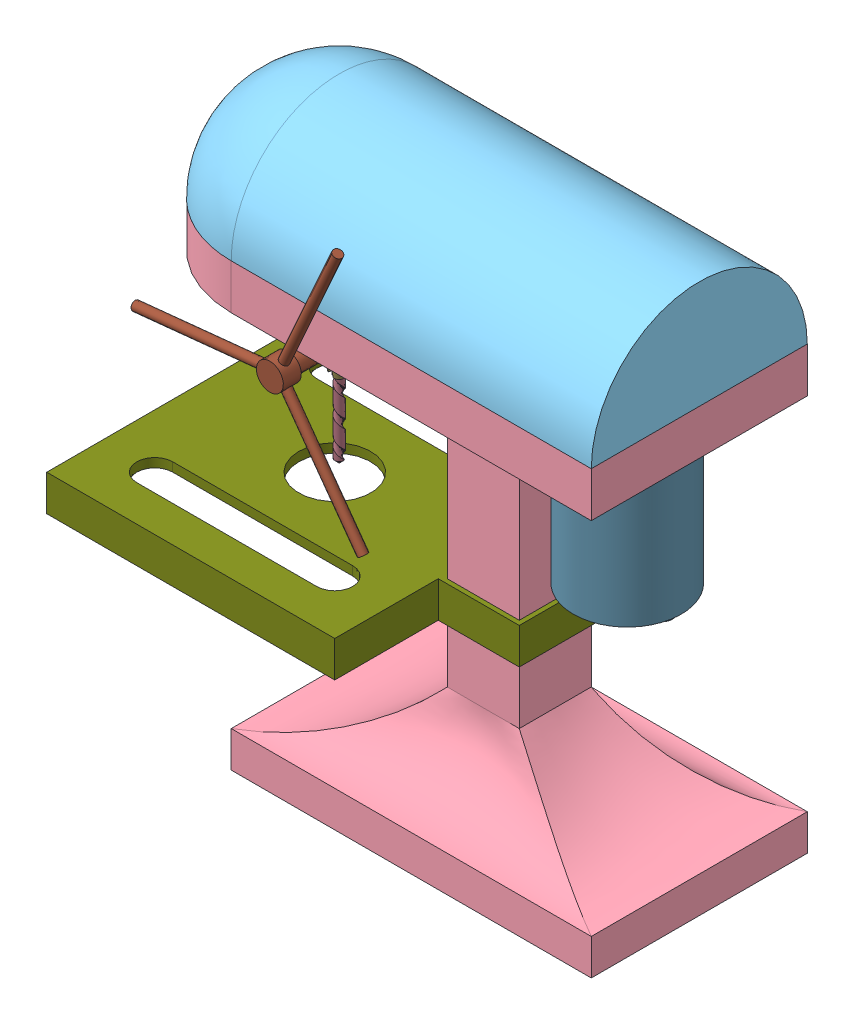
SolidWorks assembly Drill_Press, configuration Default. Lengths in mm.
Overall size (179.6 193.68 101.6).
16 component instances, 16 part files, 33 mates.
Components (placement in the parent):
- drill_slider-1: drill_slider [Default] at (-63.5 37.4244 0) size (19.05 50.8 19.05)
- drill_top_shaft-1: drill_top_shaft [Default] at (-63.5 28.575 0) x (0.204531 0 0.97886) z (-0.97886 0 0.204531) size (19.05 60.32 19.05)
- drill_bottom_shaft-2: drill_bottom_shaft [Default] at (-63.5 35.8369 0) x (0.204531 0 0.97886) z (-0.97886 0 0.204531) size (12.7 50.8 12.7)
- drill_body-1: drill_body [Default] at origin size (165.1 155.58 76.2)
- drill_lid-1: drill_lid [Default] at (63.5 15.875 0) size (165.1 38.1 76.2)
- drill_pulleys-1: drill_pulleys [Default] at (-6.35 3.175 0) x (-0.999458 0 0.032912) z (-0.032912 0 -0.999458) size (44.45 33.34 44.45)
- drill_pulley_2-1: drill_pulley_2 [Default] at (38.1 3.175 0) x (-0.986093 0 0.166196) z (-0.166196 0 -0.986093) size (44.45 33.34 44.45)
- drill_spacer-1: drill_spacer [Default] at (-12.7 31.75 0) size (120.65 3.17 19.05)
- drill_belt_main-1: drill_belt_main [Default] at (15.875 4.7625 0) size (76.2 6.35 44.45)
- drill_belt_secondary-1: drill_belt_secondary [Default] at (-34.925 28.575 0) size (76.2 3.17 19.05)
- drill_gear-1: drill_gear [Default] at (-43.5252 -6.35 -3.175) x (-0.101851 0.9948 0) z (0 0 1) size (89.58 77.57 57.15)
- drill_bit_grip-1: drill_bit_grip [Default] at (-63.5 -14.9631 0) x (-0.204531 0 -0.97886) z (0.97886 0 -0.204531) size (19.05 22.23 19.05)
- drill_bit-1: drill_bit [Default] at (-63.5 -26.8693 0) x (-0.949983 0 -0.312301) z (0.312301 0 -0.949983) size (3.67 38.1 3.23)
- drill_motor-1: drill_motor [Default] at (38.1 0 0) size (38.1 53.98 38.1)
- drill_motor_shaft-1: drill_motor_shaft [Default] at (38.1 6.35 0) x (-0.986093 0 0.166196) z (-0.166196 0 -0.986093) size (6.35 57.15 6.35)
- drill_platform-1: drill_platform [Default] at (-65.0875 -68.5214 0) x (0 0 1) z (-1 0 0) size (101.6 12.7 130.18)
Mates (geometry in assembly coordinates):
- Coincident3: coincident aligned: circle of drill_slider-1; circle of drill_bottom_shaft-2
- Concentric1: concentric aligned: cylinder of drill_top_shaft-1 through (-63.5 -23.8125 0) axis (0 1 0) radius 4.7625; cylinder of drill_bottom_shaft-2 through (-63.5 -14.9631 0) axis (0 1 0) radius 4.7625
- Coincident4: coincident anti-aligned: plane of drill_top_shaft-1 through (-57.6089 -19.05 -2.8527) normal (-0.204531 0 -0.97886); plane of drill_bottom_shaft-2 through (-57.6089 35.8369 -2.8527) normal (0.204531 0 0.97886)
- Coincident5: coincident anti-aligned: line of drill_body-1 through (63.5 15.875 -38.1) axis (-1 0 0); line of drill_lid-1 through (-63.5 15.875 -38.1) axis (1 0 0)
- Coincident6: coincident: point of drill_body-1; point of drill_lid-1
- Coincident7: coordinate: point of drill_body-1; point of assembly
- Coincident12: coincident anti-aligned: circle of drill_body-1; circle of drill_pulley_2-1
- Coincident15: coincident anti-aligned: circle of drill_body-1; circle of drill_pulleys-1
- Coincident16: coincident aligned: circle of drill_pulleys-1; circle of drill_spacer-1
- Coincident17: coincident aligned: circle of drill_top_shaft-1; circle of drill_spacer-1
- Coincident21: coincident aligned: circle of drill_pulleys-1; circle of drill_belt_main-1
- Coincident22: coincident aligned: circle of drill_pulley_2-1; circle of drill_belt_main-1
- Coincident23: coincident aligned: circle of drill_top_shaft-1; circle of drill_belt_secondary-1
- Coincident24: coincident aligned: circle of drill_pulleys-1; circle of drill_belt_secondary-1
- Coincident25: coincident aligned: circle of drill_body-1; circle of drill_gear-1
- RackPinionMate1: rack pinion = 25.4 mm: line of drill_slider-1 through (-56.2252 -13.3756 -3.175) axis (0 1 0); circle of drill_gear-1
- Coincident27: coincident anti-aligned: plane of drill_bottom_shaft-2 through (-63.5 35.8369 0) normal (-0.97886 0 0.204531); plane of drill_bit_grip-1 through (-63.5 -14.9631 0) normal (0.97886 0 -0.204531)
- Concentric2: concentric aligned: circle of drill_bottom_shaft-2; circle of drill_bit_grip-1
- Coincident28: coincident anti-aligned: plane of drill_bottom_shaft-2 through (-63.5 -14.9631 0) normal (0 -1 0); plane of drill_bit_grip-1 through (-63.5 -14.9631 0) normal (0 1 0)
- Coincident29: coincident aligned: circle of drill_pulley_2-1; circle of drill_spacer-1
- Coincident31: coincident: line of drill_bit_grip-1 through (-63.0042 -18.1381 -1.5081) axis (0 -1 0); plane of drill_bit-1 through (-62.1335 -31.6318 -1.2219) normal (0.312301 0 -0.949983)
- Coincident32: coincident: line of drill_bit_grip-1 through (-65.0539 -18.1381 0.3247) axis (0 -1 0); plane of drill_bit-1 through (-65.2414 -31.6318 -0.5725) normal (-0.97886 0 0.204531)
- Coincident33: coincident: line of drill_bit_grip-1 through (-62.4418 -18.1381 1.1834) axis (0 -1 0); plane of drill_bit-1 through (-63.1251 -31.6318 1.7943) normal (0.666559 0 0.745452)
- Distance1: distance = 0.7937 mm: point of drill_bit_grip-1; line of drill_bit-1 through (-61.7586 -37.9818 0.5725) axis (-0.745452 0 0.666559)
- GearMate1: gear = 12.7 : 38.1 mm: cylinder of drill_pulleys-1 through (-6.35 11.1125 0) axis (0 -1 0) radius 19.05; cylinder of drill_pulley_2-1 through (38.1 11.1125 0) axis (0 -1 0) radius 6.35
- GearMate2: gear = 12.7 : 12.7 mm: cylinder of drill_top_shaft-1 through (-63.5 34.925 0) axis (0 -1 0) radius 6.35; cylinder of drill_pulleys-1 through (-6.35 34.925 0) axis (0 -1 0) radius 6.35
- Coincident37: coincident aligned: circle of drill_body-1; circle of drill_motor-1
- Coincident38: coincident aligned: plane of drill_body-1 through (0 0 0) normal (0 0 1); plane of drill_motor-1 through (38.1 0 0) normal (0 0 1)
- Coincident40: coincident aligned: plane of drill_pulley_2-1 through (38.1 3.175 0) normal (-0.166196 0 -0.986093); plane of drill_motor_shaft-1 through (38.1 6.35 0) normal (-0.166196 0 -0.986093)
- Coincident41: coincident aligned: line of drill_body-1 through (-63.5 15.875 38.1) axis (1 0 0); line of drill_lid-1 through (-63.5 15.875 38.1) axis (1 0 0)
- Coincident42: coincident aligned: line of drill_body-1 through (-12.7 -101.6 -12.7) axis (0 1 0); line of drill_platform-1 through (-12.7 -81.2214 -12.7) axis (0 1 0)
- Coincident45: coincident aligned: line of drill_body-1 through (12.7 -101.6 12.7) axis (0 1 0); line of drill_platform-1 through (12.7 -81.2214 12.7) axis (0 1 0)
- Coincident46: coincident aligned: circle of drill_motor-1; circle of drill_motor_shaft-1
